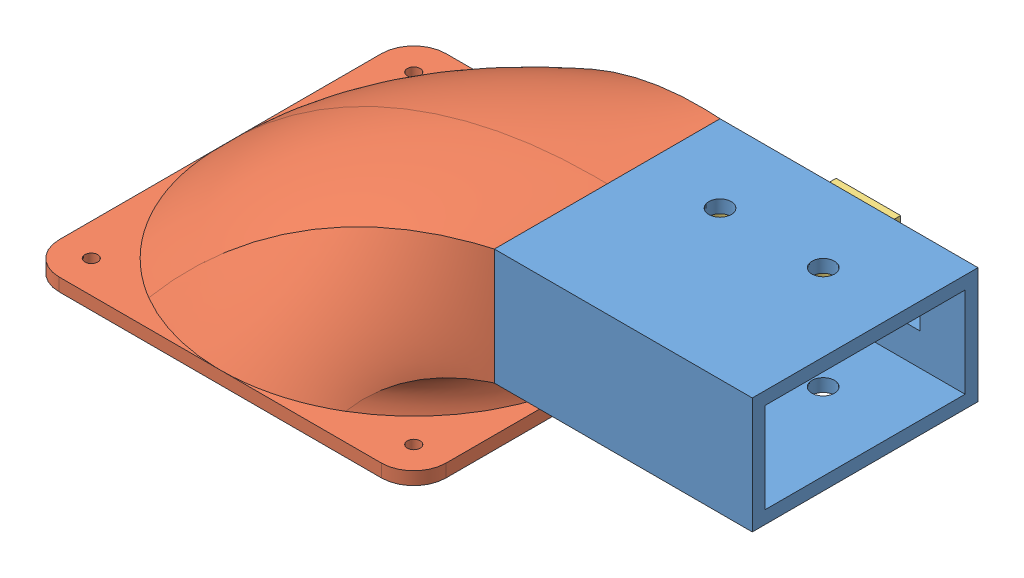
SolidWorks assembly Sub_salida_aire, configuration Predeterminado. Lengths in mm.
Overall size (137.24 27.54 60.72).
3 component instances, 3 part files, 9 mates.
Components (placement in the parent):
- ducto_sensor-1: ducto_sensor [Predeterminado] at (70 18 0) x (0 0 -1) z (0 1 0) size (35.49 78 18.62)
- ducto_ventilador-1: ducto_ventilador [Predeterminado] at origin size (63.93 27.54 60.72)
- sgp30-1: sgp30 [Predeterminado] at (50 21 -5.5) x (1 0 0) z (0 0 -1) size (24 8 27)
Mates (geometry in assembly coordinates):
- Coincidente1: coincident aligned: plane of ducto_ventilador-1 through (0 0 0) normal (0 1 0); plane of assembly through (0 0 0) normal (0 1 0)
- Coincidente2: coincident aligned: plane of ducto_ventilador-1 through (0 0 0) normal (0 0 1); plane of assembly through (0 0 0) normal (0 0 1)
- Coincidente3: coincident aligned: plane of ducto_ventilador-1 through (0 0 0) normal (1 0 0); plane of assembly through (0 0 0) normal (1 0 0)
- Coincidente4: coincident anti-aligned: plane of ducto_sensor-1 through (30 9 17.5) normal (0 -1 0); line of ducto_ventilador-1 through (30 9 17.5) axis (0 0 -1)
- Coincidente5: coincident anti-aligned: plane of ducto_sensor-1 through (30 18 0) normal (-1 0 0); plane of ducto_ventilador-1 through (30 0 0) normal (1 0 0)
- Coincidente6: coincident: plane of ducto_sensor-1 through (30 9 17.5) normal (0 0 1); line of ducto_ventilador-1 through (30 27 17.5) axis (0 -1 0)
- Concéntrica4: concentric anti-aligned: circle of ducto_sensor-1; circle of sgp30-1
- Concéntrica5: concentric aligned: circle of ducto_sensor-1; circle of sgp30-1
- Coincidente9: coincident anti-aligned: plane of ducto_sensor-1 through (30 25 15.5) normal (0 -1 0); plane of sgp30-1 through (42 25 -13.5) normal (0 1 0)
